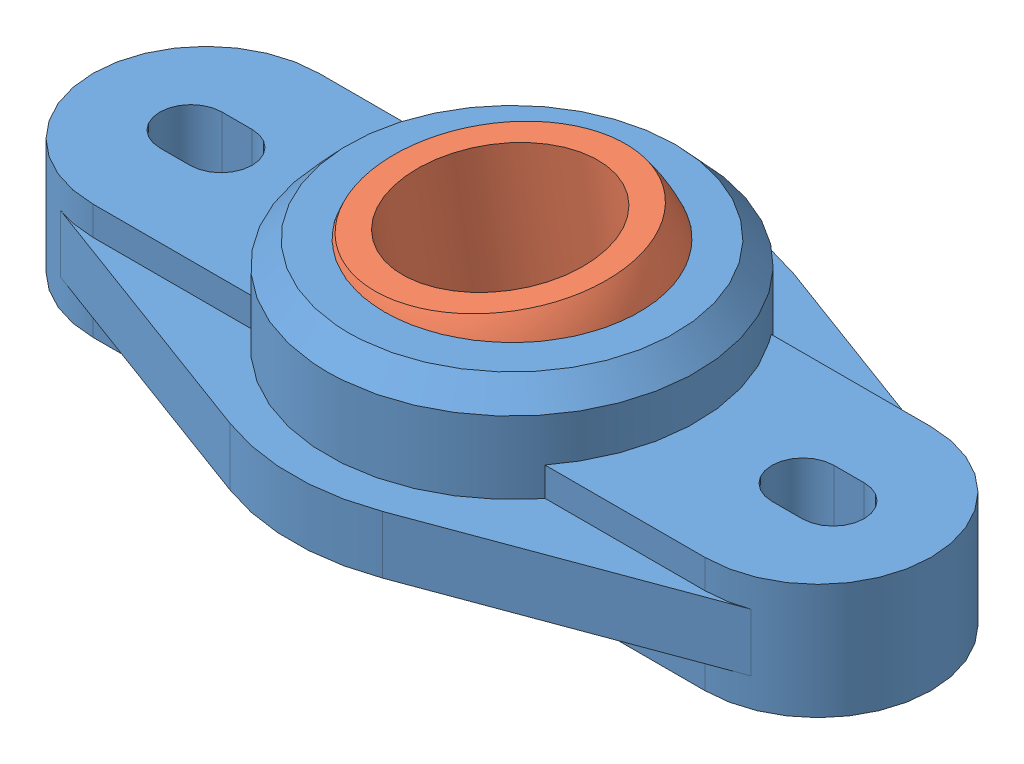
SolidWorks assembly igubal_SphericalFlange, configuration Default. Lengths in mm.
Overall size (72.61 19.17 38).
2 component instances, 2 part files, 1 mates.
Components (placement in the parent):
- igubal_SphericalFlange_Bearing-1: igubal_SphericalFlange_Bearing [Default] at (31.8431 39.3288 52.255) size (72.61 15.75 38)
- igubal_SphericalFlange_Ball-1: igubal_SphericalFlange_Ball [Default] at (31.8431 45.3296 52.255) x (-0.32329 -0.099038 0.941103) z (0.085238 -0.993513 -0.075272) size (24 24 12.7)
Mates (geometry in assembly coordinates):
- Concentric1: concentric: sphere of igubal_SphericalFlange_Bearing-1; sphere of igubal_SphericalFlange_Ball-1
